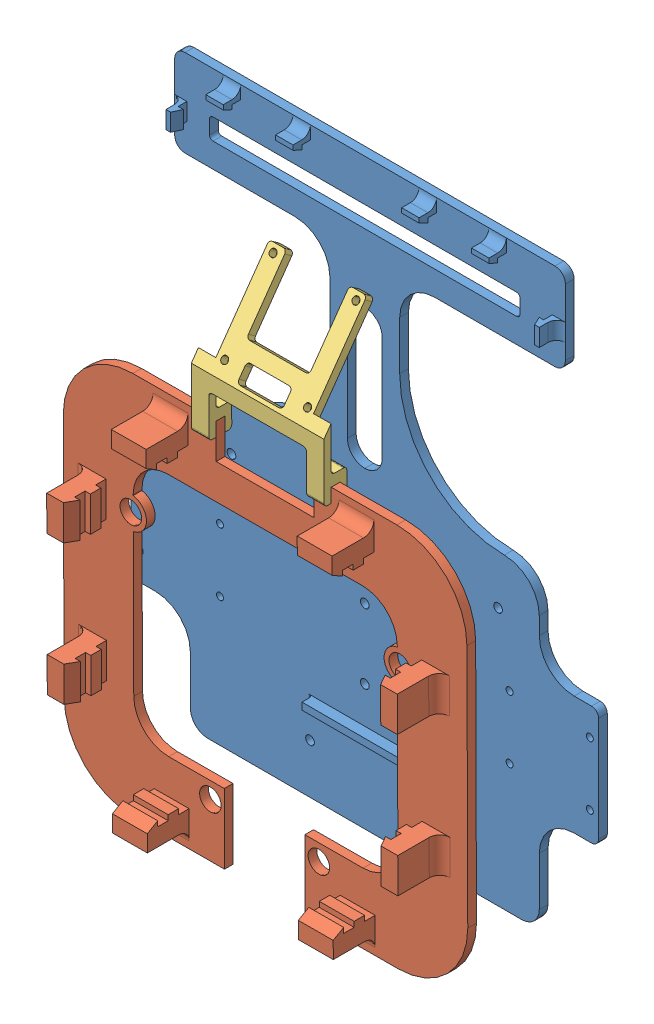
SolidWorks assembly Ensamblaje1, configuration Predeterminado. Lengths in mm.
Overall size (134 168.36 43.37).
3 component instances, 3 part files, 5 mates.
Components (placement in the parent):
- Base-2: Base [Predeterminado] at (-33.5975 -40.0134 159.4179) size (134 167 7.5)
- PiezaSuperior-3: PiezaSuperior [Predeterminado] at (-28.2977 -51.6679 190.7851) x (-0.999994 -0.003349 0) z (0 0 -1) size (115.69 110 14.5)
- Pantalla-2: Pantalla [Predeterminado] at (-33.4518 28.421 184.1063) x (0.999994 0.003349 0) z (0.001945 -0.580901 -0.813972) size (38 43.36 14.74)
Mates (geometry in assembly coordinates):
- Concéntrica8: concentric aligned: cylinder of Base-2 through (-71.7975 -31.5134 159.4179) axis (0 0 1) radius 1.25; cylinder of PiezaSuperior-3 through (-71.7975 -31.5134 188.2851) axis (0 0 1) radius 3.1
- Coincidente1: coincident anti-aligned: plane of PiezaSuperior-3 through (-28.4819 3.3318 188.2851) normal (-0.003349 0.999994 0); plane of Pantalla-2 through (-47.3676 3.2686 186.2851) normal (0.003349 -0.999994 0)
- Perpendicular1: perpendicular: plane of PiezaSuperior-3 through (-28.4819 3.3318 188.2851) normal (-0.003349 0.999994 0); plane of Pantalla-2 through (-47.3442 -3.7314 190.3188) normal (0.999994 0.003349 0)
- Coincidente2: coincident: point of PiezaSuperior-3; point of Pantalla-2
- Coincidente3: coincident: point of PiezaSuperior-3; point of Pantalla-2
